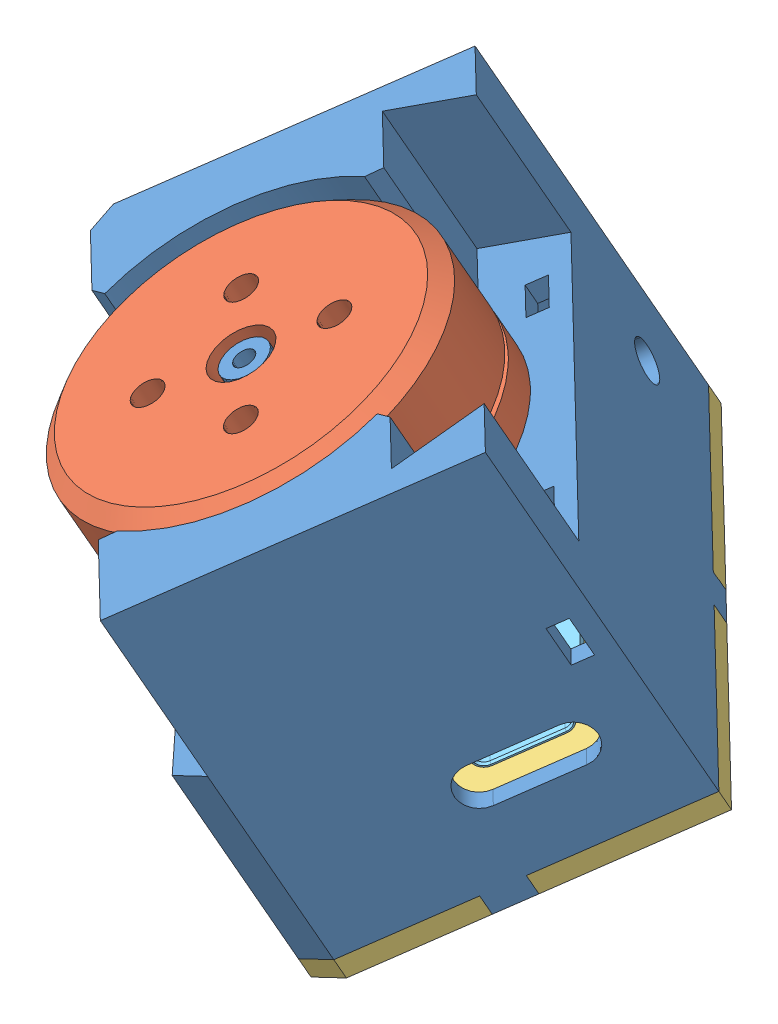
SolidWorks assembly super knob lite, configuration 默认. Lengths in mm.
Overall size (70.29 53.58 71.36).
7 component instances, 6 part files, 13 mates.
Components (placement in the parent):
- lite_shell-1: lite_shell [默认] at (-87.6916 -48.6136 17.984) x (0.717336 -0.043903 0.695343) z (0.303783 -0.878443 -0.368855) size (50 36 39)
- motor2804-2: motor2804 [默认] at (-66.4773 -30.5867 33.1904) x (0.640818 0.474884 -0.60319) z (0.303783 -0.878443 -0.368855) size (35 35 16)
- lite_shell_right-1: lite_shell_right [默认] at (-87.6916 -48.6136 17.984) x (0.717336 -0.043903 0.695343) z (0.303783 -0.878443 -0.368855) size (50 36 13)
- Screen_st77352-1: Screen_st77352 [默认] at (-156.333 -10.2644 -36.6888) x (0.303783 -0.878443 -0.368855) z (-0.672367 -0.47196 0.570242) size (20 44 4.09)
- SuperKnobLite-1: SuperKnobLite [默认] at (-14.5841 9.6975 -88.1223) x (0.717336 -0.043903 0.695343) z (0.303783 -0.878443 -0.368855) size (43.3 23 5.96)
- hexagon socket countersunk head screws gb-1: hexagon socket countersunk head screws gb [GB_FASTENER_SCREWS_HSCHS M3X8-N] at (-51.4308 -54.8075 29.8011) x (-0.303783 0.878443 0.368855) z (-0.606436 -0.476879 0.636256) size (8 5.54 5.54)
- hexagon socket countersunk head screws gb-2: hexagon socket countersunk head screws gb [GB_FASTENER_SCREWS_HSCHS M3X8-N] at (-64.9399 -54.3212 16.4435) x (-0.303783 0.878443 0.368855) z (-0.49918 -0.47651 0.723711) size (8 5.54 5.54)
Mates (geometry in assembly coordinates):
- 重合6: coincident anti-aligned: plane of lite_shell-1 through (-87.6916 -48.6136 17.984) normal (-0.303783 0.878443 0.368855); plane of motor2804-2 through (-61.9206 -43.7633 27.6576) normal (0.303783 -0.878443 -0.368855)
- 同心1: concentric anti-aligned: cylinder of motor2804-2 through (-60.4017 -48.1555 25.8133) axis (-0.303783 0.878443 0.368855) radius 3; cylinder of lite_shell-1 through (-66.3254 -31.0259 33.006) axis (0.303783 -0.878443 -0.368855) radius 2.25
- 重合12: coincident anti-aligned: plane of lite_shell-1 through (-81.0084 -67.9393 9.8692) normal (0.303783 -0.878443 -0.368855); plane of lite_shell_right-1 through (-81.0084 -67.9393 9.8692) normal (-0.303783 0.878443 0.368855)
- 重合13: coincident anti-aligned: plane of lite_shell-1 through (-70.0551 -61.8451 -1.0457) normal (0.627013 0.475826 -0.616802); plane of lite_shell_right-1 through (-70.6627 -60.0882 -0.308) normal (-0.627013 -0.475826 0.616802)
- 重合14: coincident aligned: plane of lite_shell-1 through (-87.0841 -50.3705 17.2463) normal (-0.717336 0.043903 -0.695343); plane of lite_shell_right-1 through (-79.1468 -68.7446 7.8979) normal (-0.717336 0.043903 -0.695343)
- 同心9: concentric aligned: cylinder of lite_shell-1 through (-77.1518 -58.7581 18.2909) axis (0.672367 0.47196 -0.570242) radius 0.5; cylinder of Screen_st77352-1 through (-76.2028 -58.0919 17.486) axis (0.672367 0.47196 -0.570242) radius 1
- 重合17: coincident aligned: plane of lite_shell-1 through (-81.0084 -67.9393 9.8692) normal (0.303783 -0.878443 -0.368855); plane of Screen_st77352-1 through (-46.5021 -69.83 42.7909) normal (0.303783 -0.878443 -0.368855)
- 重合18: coincident anti-aligned: plane of lite_shell-1 through (-86.6671 -47.8944 17.1151) normal (0.672367 0.47196 -0.570242); plane of Screen_st77352-1 through (-75.1744 -53.5872 25.9543) normal (-0.672367 -0.47196 0.570242)
- 同心10: concentric anti-aligned: cylinder of lite_shell-1 through (-68.7353 -43.3463 21.0518) axis (0.303783 -0.878443 -0.368855) radius 1.5; cylinder of SuperKnobLite-1 through (-65.8493 -51.6915 17.5477) axis (-0.303783 0.878443 0.368855) radius 1.6
- 同心11: concentric anti-aligned: cylinder of lite_shell-1 through (-55.1059 -44.1804 34.2633) axis (0.303783 -0.878443 -0.368855) radius 1.5; cylinder of SuperKnobLite-1 through (-52.2199 -52.5256 30.7592) axis (-0.303783 0.878443 0.368855) radius 1.6
- 重合19: coincident anti-aligned: plane of lite_shell-1 through (-59.0346 -52.1085 24.1535) normal (0.303783 -0.878443 -0.368855); plane of SuperKnobLite-1 through (-64.38 -43.8113 -0.0092) normal (-0.303783 0.878443 0.368855)
- 同心13: concentric aligned: cylinder of lite_shell-1 through (-55.1059 -44.1804 34.2633) axis (0.303783 -0.878443 -0.368855) radius 1.5; cylinder of hexagon socket countersunk head screws gb-1 through (-51.2525 -55.3232 29.5845) axis (0.303783 -0.878443 -0.368855) radius 1.5
- 同心14: concentric aligned: cylinder of lite_shell-1 through (-68.7353 -43.3463 21.0518) axis (0.303783 -0.878443 -0.368855) radius 1.5; cylinder of hexagon socket countersunk head screws gb-2 through (-64.7616 -54.8369 16.2269) axis (0.303783 -0.878443 -0.368855) radius 1.5
